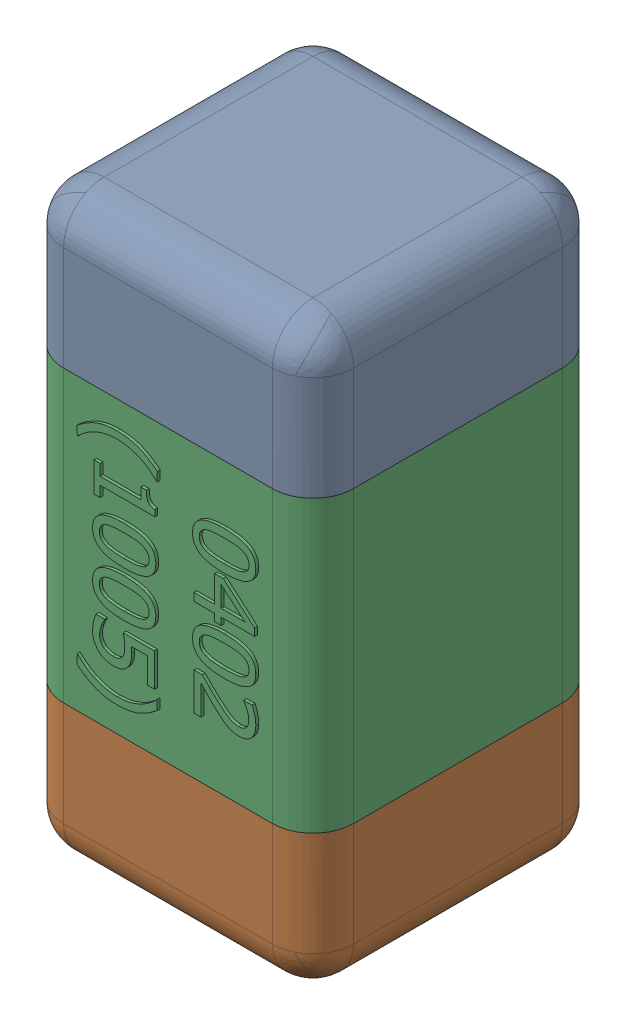
SolidWorks assembly C15, configuration Standard. Lengths in mm.
Overall size (0.51 1.01 0.51).
4 component instances, 3 part files, 0 mates.
Components (placement in the parent):
- C15-subassembly-1-1: C15-subassembly-1 [Standard] at (-1.1 18.0999 0) x (0 -1 0) z (0 0 1) size (1.01 0.51 0.51)
  - User Library-0402_Cap-1: User Library-0402_Cap [Standard] at origin size (0.26 0.51 0.51)
  - User Library-0402_Cap-1-1: User Library-0402_Cap-1 [Standard] at origin size (0.26 0.5 0.51)
  - User Library-0402_Cap-2-1: User Library-0402_Cap-2 [Standard] at origin size (0.5 0.5 0.51)
